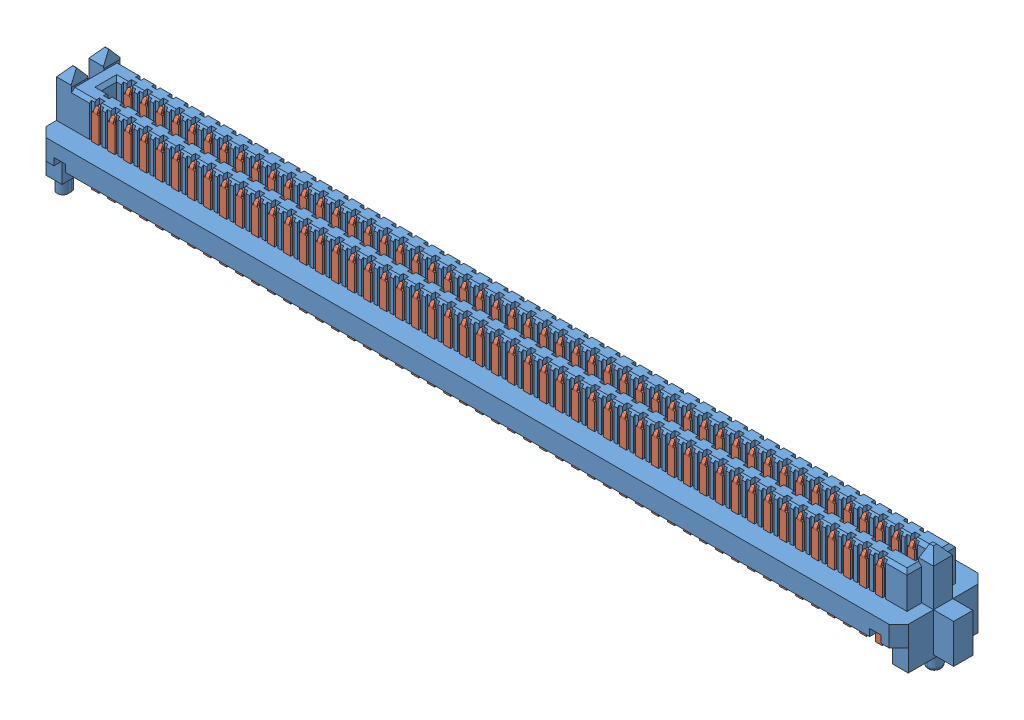
SolidWorks assembly SEAM_50_03_5_L_04_2_A_K_TR, configuration Default. Lengths in mm.
Overall size (70.08 8.38 7.06).
4 component instances, 4 part files, 0 mates.
Components (placement in the parent):
- _SEAM_50_03_5_L_04_1_A_K_TR_body_2-1: _SEAM_50_03_5_L_04_1_A_K_TR_body_2 [Default] at origin size (70.08 8.38 7.06)
- _SEAM_50_03_5_L_04_1_A_K_TR_conn_4-1: _SEAM_50_03_5_L_04_1_A_K_TR_conn_4 [Default] at origin size (67.97 5.75 6.55)
- _SEAM_K_Pad_04_6-1: _SEAM_K_Pad_04_6 [Default] at (0 2.7432 0) size (5.99 0.13 5.99) (hidden)
- _SEAM_Triangle_8-1: _SEAM_Triangle_8 [Default] at (32.2834 1.3462 -1.6764) x (-1 0 0) z (0 0 -1) size (1.02 1.27 0.13)
